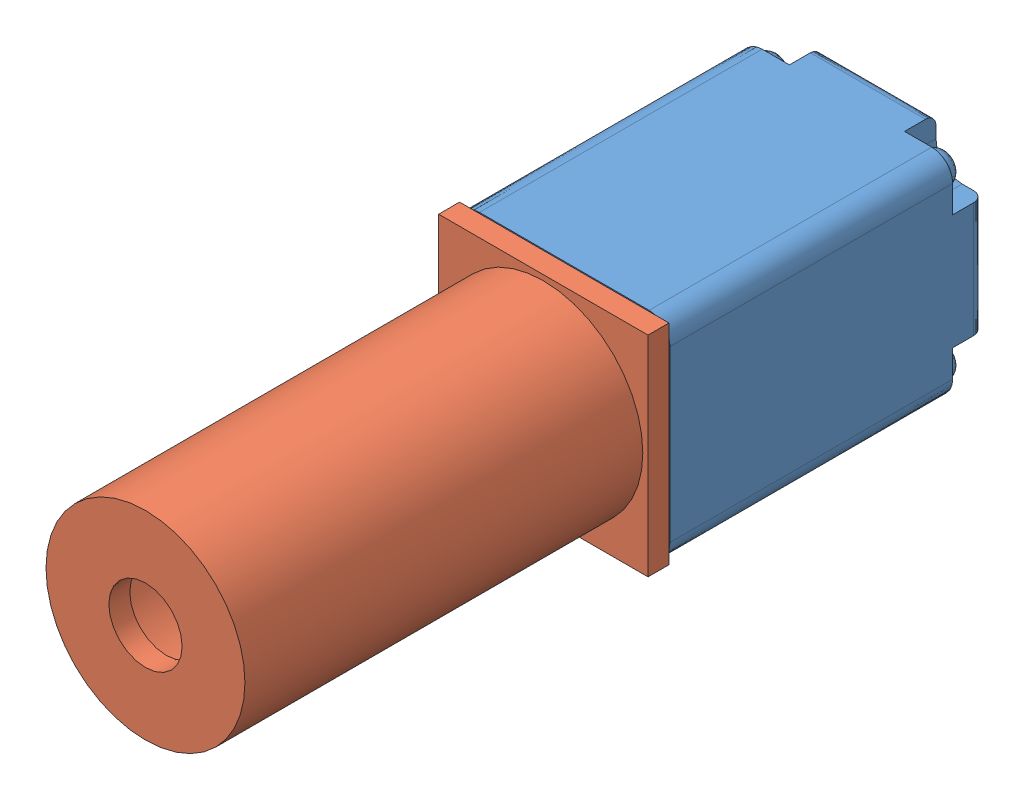
SolidWorks assembly Vacuum manipulator, configuration По умолчанию. Lengths in mm.
Overall size (20.2 20.2 70).
2 component instances, 2 part files, 3 mates.
Components (placement in the parent):
- FL20STH30-0604A-1: FL20STH30-0604A [По умолчанию] at origin size (20.2 20.2 45)
- Vacuum connector-1: Vacuum connector [По умолчанию] at (0 0 30) x (1 0 0) z (0 -1 0) size (20 40 20)
Mates (geometry in assembly coordinates):
- Концентричный1: concentric anti-aligned: cylinder of FL20STH30-0604A-1 through (0 0 45) axis (0 0 -1) radius 2; cylinder of Vacuum connector-1 through (0 0 30) axis (0 0 1) radius 3.5
- Совпадение1: coincident anti-aligned: plane of FL20STH30-0604A-1 through (0 0 30) normal (0 0 1); plane of Vacuum connector-1 through (0 0 30) normal (0 0 -1)
- Параллельность1: parallel aligned: plane of FL20STH30-0604A-1 through (10.1 10.1 30) normal (0 1 0); plane of Vacuum connector-1 through (10 10 70) normal (0 1 0)
